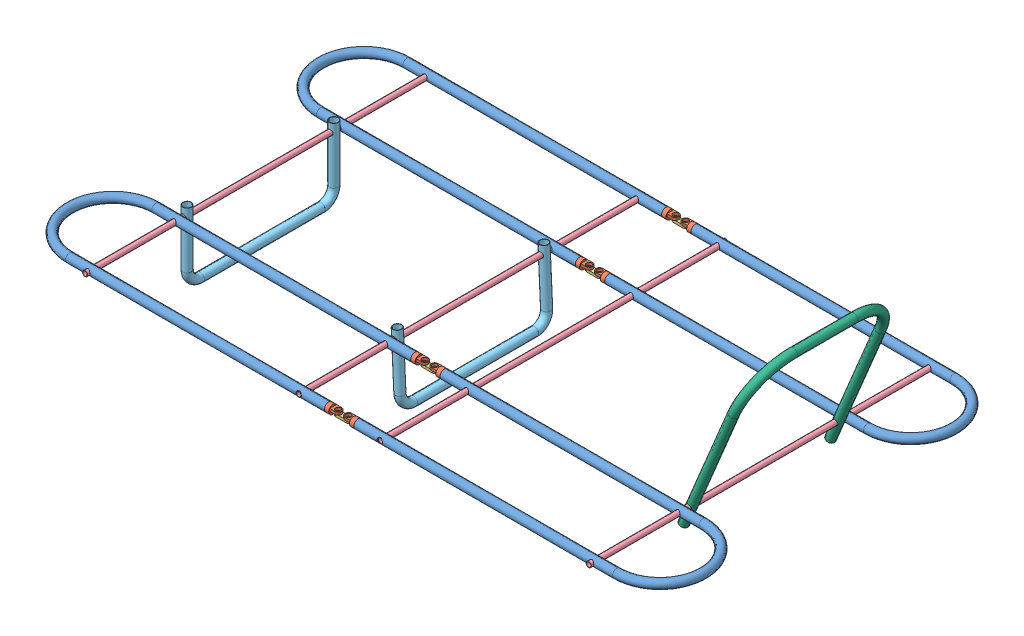
SolidWorks assembly Frame, configuration Default. Lengths in mm.
Overall size (1488 486.47 807.68).
25 component instances, 6 part files, 9 mates.
Components (placement in the parent):
- FrameOneSideNoAnim-1: FrameOneSideNoAnim [Default] at (577.8554 752.7862 1416.0585) size (1488 20 220)
  - F1-1: F1 [Default<As Welded>] at (120.0879 35.9229 252.3231) size (710 20 220)
  - H1-1: H1 [Default] at (120.0879 35.9229 252.3231) x (0 1 0) z (-1 0 0) size (20 20 40)
  - H2-1: H2 [Default] at (166.0879 29.9229 252.3231) x (1 0 0) z (0 1 0) size (36 12 6)
  - H1-2: H1 [Default] at (188.0879 35.9229 252.3231) x (0 1 0) z (1 0 0) size (20 20 40)
  - H2-2: H2 [Default] at (166.0879 29.9229 52.3231) x (1 0 0) z (0 1 0) size (36 12 6)
  - H1-4: H1 [Default] at (188.0879 35.9229 52.3231) x (0 1 0) z (1 0 0) size (20 20 40)
  - H1-6: H1 [Default] at (120.0879 35.9229 52.3231) x (0 1 0) z (-1 0 0) size (20 20 40)
  - F1-2: F1 [Default<As Welded>] at (188.0879 35.9229 52.3231) x (-1 0 0) z (0 0 -1) size (710 20 220)
- FrameOneSideNoAnim-2: FrameOneSideNoAnim [Default] at (577.8554 752.7862 834.315) size (1488 20 220)
  - F1-1: F1 [Default<As Welded>] at (120.0879 35.9229 252.3231) size (710 20 220)
  - H1-1: H1 [Default] at (120.0879 35.9229 252.3231) x (0 1 0) z (-1 0 0) size (20 20 40)
  - H2-1: H2 [Default] at (166.0879 29.9229 252.3231) x (1 0 0) z (0 1 0) size (36 12 6)
  - H1-2: H1 [Default] at (188.0879 35.9229 252.3231) x (0 1 0) z (1 0 0) size (20 20 40)
  - H2-2: H2 [Default] at (166.0879 29.9229 52.3231) x (1 0 0) z (0 1 0) size (36 12 6)
  - H1-4: H1 [Default] at (188.0879 35.9229 52.3231) x (0 1 0) z (1 0 0) size (20 20 40)
  - H1-6: H1 [Default] at (120.0879 35.9229 52.3231) x (0 1 0) z (-1 0 0) size (20 20 40)
  - F1-2: F1 [Default<As Welded>] at (188.0879 35.9229 52.3231) x (-1 0 0) z (0 0 -1) size (710 20 220)
- F2-1: F2 [Default] at (147.9433 788.709 883.2223) x (0.974991 0.222245 0) z (0 0 1) size (12 12 800)
- F2-2: F2 [Default] at (637.9433 788.709 877.7586) x (-0.420932 0.907092 0) z (0 0 1) size (12 12 800)
- F2-3: F2 [Default] at (825.9433 788.709 876.0371) x (-0.580942 -0.813945 0) z (0 0 1) size (12 12 800)
- F2-4: F2 [Default] at (1315.9433 788.709 883.7191) x (-0.357466 -0.933926 0) z (0 0 1) size (12 12 800)
- F3-1: F3 [Default<As Welded>] at (147.9398 808.709 1446.6074) x (0 0 -1) z (1 0.000171 0) size (400 170 20)
- F3-2: F3 [Default<As Welded>] at (636.9986 808.6867 1448.5287) x (0 0 -1) z (0.998884 0.047235 0) size (400 170 20)
- F4-1: F4 [Default<As Welded>] at (1296.7167 742.5534 1103.7931) x (0 0 -1) z (0.923112 -0.38453 0) size (360 410 20)
Mates (geometry in assembly coordinates):
- Coincident2: coincident aligned: line of FrameOneSideNoAnim-1/F1-2 through (1315.9433 788.709 1730.7992) axis (0 0 -1); line of FrameOneSideNoAnim-2/F1-2 through (1315.9433 788.709 1149.0557) axis (0 0 -1)
- Coincident3: coincident aligned: line of FrameOneSideNoAnim-1/F1-1 through (147.9433 788.709 1405.964) axis (0 0 1); line of FrameOneSideNoAnim-2/F1-1 through (147.9433 788.709 824.2205) axis (0 0 1)
- Coincident5: coincident anti-aligned: line of FrameOneSideNoAnim-1/F1-1 through (147.9433 788.709 1405.964) axis (0 0 1); line of F2-1 through (147.9433 788.709 1683.2223) axis (0 0 -1)
- Coincident6: coincident anti-aligned: line of FrameOneSideNoAnim-1/F1-1 through (637.9433 788.709 1422.8612) axis (0 0 1); line of F2-2 through (637.9433 788.709 1677.7586) axis (0 0 -1)
- Coincident7: coincident aligned: line of FrameOneSideNoAnim-1/F1-2 through (825.9433 788.709 1713.902) axis (0 0 -1); line of F2-3 through (825.9433 788.709 1676.0371) axis (0 0 -1)
- Coincident8: coincident aligned: line of FrameOneSideNoAnim-2/F1-2 through (1315.9433 788.709 1149.0557) axis (0 0 -1); line of F2-4 through (1315.9433 788.709 1683.7191) axis (0 0 -1)
- Concentric1: concentric anti-aligned: cylinder of F2-1 through (147.9433 788.709 1683.2223) axis (0 0 -1) radius 6; cylinder of F3-1 through (147.9433 788.709 1496.6074) axis (0 0 1) radius 6.35
- Concentric2: concentric anti-aligned: cylinder of F2-2 through (637.9433 788.709 1677.7586) axis (0 0 -1) radius 5; cylinder of F3-2 through (637.9433 788.709 1498.5287) axis (0 0 1) radius 6.35
- Concentric3: concentric anti-aligned: cylinder of F2-4 through (1315.9433 788.709 1683.7191) axis (0 0 -1) radius 5; cylinder of F4-1 through (1315.9433 788.709 1503.7931) axis (0 0 1) radius 6.35
